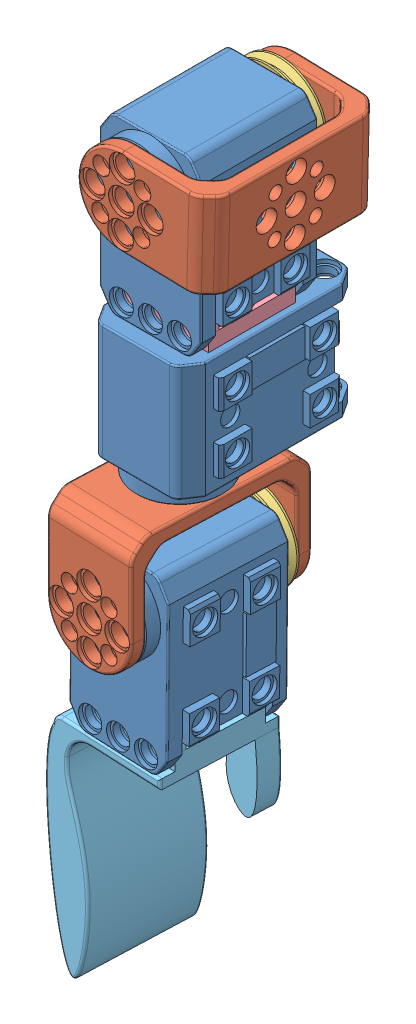
SolidWorks assembly brazoizq, configuration Predeterminado. Lengths in mm.
Overall size (39.74 158.79 45.47).
9 component instances, 5 part files, 20 mates.
Components (placement in the parent):
- XL-320-1: XL-320 [Default] at origin size (24 36 27)
- shoulder-1: shoulder [Default] x (-0.999666 0.025834 0) z (0 0 1) size (27 18 36.29)
- SP0-1: SP0 [Default] at (0.5003 -72 -7.4907) x (0.999121 -0.019629 0.03705) z (0.019616 0.999807 0.000727) size (19 3 19)
- SPU-5-1: SPU-5 [Default] at (0 -24 0) x (-1 0 0) z (0 -1 0) size (18 18 6)
- XL-320-2: XL-320 [Default] at (0 -39 6) x (1 0 0) z (0 -1 0) size (24 36 27)
- shoulder-2: shoulder [Default] at (0 -72 6) x (0 -1 0) z (-0.037057 0 0.999313) size (27 18 36.29)
- XL-320-3: XL-320 [Default] at (0 -72 6) x (0.999264 -0.00987 0.037055) z (-0.037057 0 0.999313) size (24 36 27)
- hand-1: hand [left] at (-16.5629 -91.9373 -24.5161) x (0.037057 0 -0.999313) z (-0.009863 -0.999951 -0.000366) size (32.52 30.29 56.19)
- SP0-2: SP0 [Default] at (0 0 -13.5) x (1 0 0) z (0 1 0) size (19 3 19)
Mates (geometry in assembly coordinates):
- Concéntrica1: concentric aligned: cylinder of XL-320-1 through (0 0 15) axis (0 0 1) radius 2.8; cylinder of shoulder-1 through (0 0 18) axis (0 0 1) radius 2.15
- Coincidente1: coincident anti-aligned: plane of XL-320-1 through (0 0 15) normal (0 0 1); plane of shoulder-1 through (0 0 15) normal (0 0 -1)
- Coincidente2: coincident anti-aligned: plane of XL-320-1 through (0 0 -9) normal (0 0 1); plane of SPU-5-1 through (0 -27 -9) normal (0 0 -1)
- Coincidente3: coincident aligned: plane of XL-320-1 through (-8 -27 -12) normal (0 -1 0); plane of SPU-5-1 through (0 -27 0) normal (0 -1 0)
- Concéntrica2: concentric aligned: cylinder of XL-320-1 through (-6 -24 12) axis (0 0 1) radius 2; cylinder of SPU-5-1 through (-6 -24 9) axis (0 0 1) radius 2
- Coincidente4: coincident anti-aligned: plane of SPU-5-1 through (0 -27 0) normal (0 -1 0); plane of XL-320-2 through (0 -27 6) normal (0 1 0)
- Concéntrica3: concentric anti-aligned: cylinder of SPU-5-1 through (0 -27 6) axis (0 -1 0) radius 2; cylinder of XL-320-2 through (0 -27 6) axis (0 1 0) radius 2
- Paralelo1: parallel aligned: plane of XL-320-1 through (0 0 12) normal (0 0 1); plane of XL-320-2 through (8 -27 15) normal (0 0 1)
- Coincidente6: coincident anti-aligned: plane of XL-320-2 through (0 -54 6) normal (0 -1 0); plane of shoulder-2 through (8.3268 -54 24.3211) normal (0 1 0)
- Concéntrica4: concentric aligned: cylinder of XL-320-2 through (0 -54 6) axis (0 -1 0) radius 2.8; cylinder of shoulder-2 through (0 -57 6) axis (0 -1 0) radius 2.15
- Coincidente7: coincident anti-aligned: plane of SP0-1 through (0.5559 -72 -8.9897) normal (0.037057 0 -0.999313); plane of shoulder-2 through (0.5559 -72 -8.9897) normal (-0.037057 0 0.999313)
- Concéntrica5: concentric aligned: cylinder of SP0-1 through (0.5559 -72 -8.9897) axis (0.037057 0 -0.999313) radius 2; cylinder of shoulder-2 through (0.667 -72 -11.9876) axis (0.037057 0 -0.999313) radius 2.15
- Concéntrica6: concentric aligned: cylinder of SP0-1 through (0.5559 -72 -8.9897) axis (0.037057 0 -0.999313) radius 2; cylinder of XL-320-3 through (0.4447 -72 -5.9918) axis (0.037057 0 -0.999313) radius 2
- Concéntrica7: concentric aligned: cylinder of shoulder-2 through (-0.667 -72 23.9876) axis (-0.037057 0 0.999313) radius 2.15; cylinder of XL-320-3 through (-0.5559 -72 20.9897) axis (-0.037057 0 0.999313) radius 2.8
- Coincidente8: coincident anti-aligned: plane of shoulder-2 through (-0.5559 -72 20.9897) normal (0.037057 0 -0.999313); plane of XL-320-3 through (-0.5559 -72 20.9897) normal (-0.037057 0 0.999313)
- Coincidente9: coincident anti-aligned: plane of XL-320-3 through (-0.3335 -72 14.9938) normal (0.037057 0 -0.999313); plane of hand-1 through (-0.5998 -98.9987 14.9839) normal (-0.037057 0 0.999313)
- Concéntrica8: concentric aligned: cylinder of XL-320-3 through (-6.677 -95.9396 17.7607) axis (-0.037057 0 0.999313) radius 2; cylinder of hand-1 through (-6.5658 -95.9396 14.7627) axis (-0.037057 0 0.999313) radius 2
- Concéntrica9: concentric aligned: cylinder of XL-320-3 through (5.3142 -96.0581 18.2053) axis (-0.037057 0 0.999313) radius 2; cylinder of hand-1 through (5.4254 -96.0581 15.2074) axis (-0.037057 0 0.999313) radius 2
- Coincidente10: coincident: plane of shoulder-1 through (0 0 -15) normal (0 0 1); plane of SP0-2 through (0 0 -15) normal (0 0 -1)
- Concéntrica10: concentric aligned: cylinder of shoulder-1 through (0 0 -18) axis (0 0 -1) radius 2.15; cylinder of SP0-2 through (0 0 -15) axis (0 0 -1) radius 2
